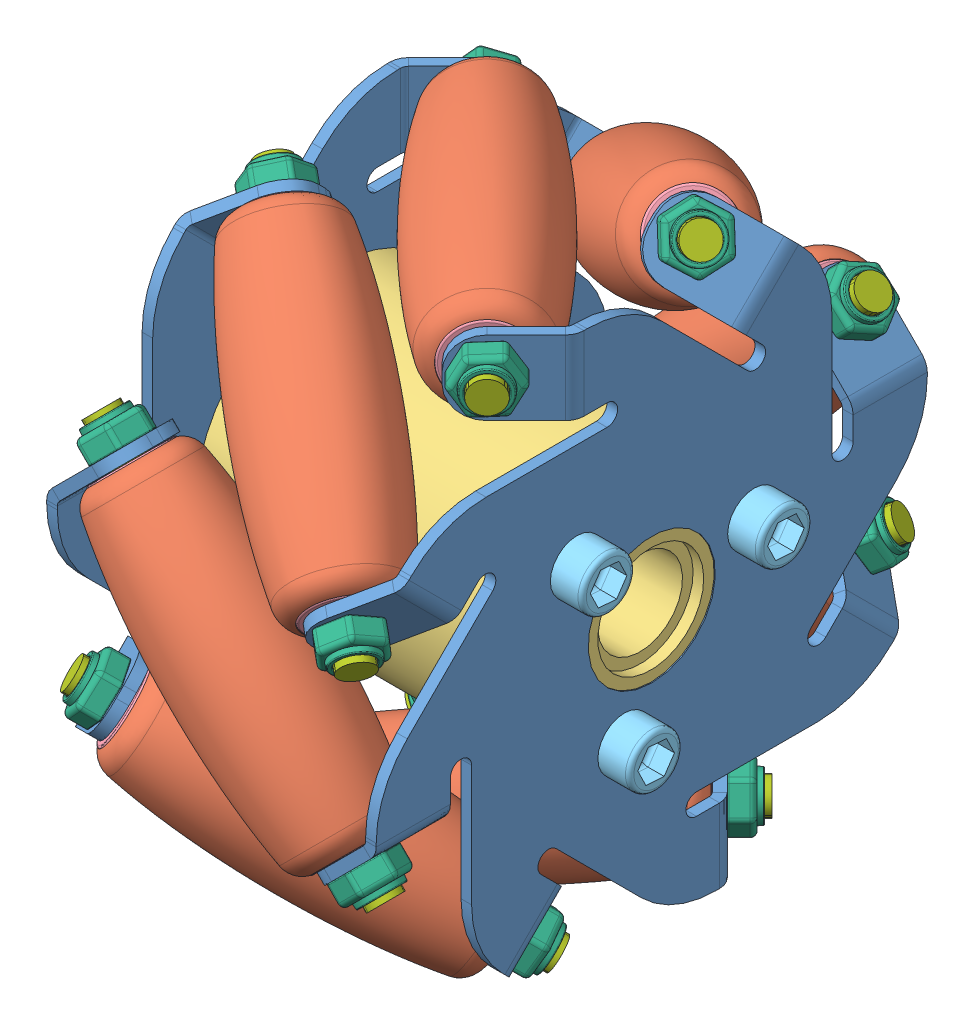
SolidWorks assembly Mecanum_Wheel_60mm_ASM, configuration Varsayılan. Lengths in mm.
Overall size (37 62 62).
57 component instances, 7 part files, 19 mates.
Components (placement in the parent):
- plate_1-1: plate_1 [Varsayılan] at (-26.0247 -30.9199 60) size (7.04 53.75 53.75)
- plate_1-2: plate_1 [Varsayılan] at (3.0696 29.3814 -0.3013) x (-1 0 0) z (0 1 0) size (7.04 53.75 53.75)
- roller-14: roller [Varsayılan] at (-11.1205 15.2872 46.4107) x (0.707107 -0.5 0.5) z (-0.228848 -0.830871 -0.50723) size (29.8 12 12)
- inner_cylinder-1: inner_cylinder [Varsayılan] at (-26.0247 -0.7238 29.8948) x (0 0.707107 -0.707107) z (1 0 0) size (26 26 31)
- liner-2: liner [Varsayılan] at (-0.849 8.0242 53.6738) x (0.666667 0.707107 -0.235702) z (-0.235702 0.5 0.833333) size (7 1 7)
- liner-3: liner [Varsayılan] at (-22.0622 23.0242 38.6738) x (0 -0.707107 -0.707107) z (-0.707107 -0.5 0.5) size (7 1 7)
- liner-4: liner [Varsayılan] at (-22.0622 22.2762 19.3102) x (0 -1 0) z (-0.707107 0 0.707107) size (7 1 7)
- liner-5: liner [Varsayılan] at (-22.0622 8.0552 6.1469) x (0 -0.707107 0.707107) z (-0.707107 0.5 0.5) size (7 1 7)
- liner-6: liner [Varsayılan] at (-22.0622 -11.3084 6.8948) x (0 0 1) z (-0.707107 0.707107 0) size (7 1 7)
- liner-7: liner [Varsayılan] at (-22.0622 -24.4717 21.1158) x (0 0.707107 0.707107) z (-0.707107 0.5 -0.5) size (7 1 7)
- liner-8: liner [Varsayılan] at (-22.0622 -23.7238 40.4794) x (0 1 0) z (-0.707107 0 -0.707107) size (7 1 7)
- liner-9: liner [Varsayılan] at (-22.0622 -9.5028 53.6427) x (0 0.707107 -0.707107) z (-0.707107 -0.5 -0.5) size (7 1 7)
- liner-10: liner [Varsayılan] at (-22.0622 9.8609 52.8948) x (0 0 -1) z (-0.707107 -0.707107 0) size (7 1 7)
- liner-11: liner [Varsayılan] at (-0.849 22.2762 40.5234) x (0.666667 0.333333 -0.666667) z (-0.235702 0.942809 0.235702) size (7 1 7)
- liner-12: liner [Varsayılan] at (-0.849 23.0552 21.1469) x (0.666667 -0.235702 -0.707107) z (-0.235702 0.833333 -0.5) size (7 1 7)
- liner-13: liner [Varsayılan] at (-0.849 9.9048 6.8948) x (0.666667 -0.666667 -0.333333) z (-0.235702 0.235702 -0.942809) size (7 1 7)
- liner-14: liner [Varsayılan] at (-0.849 -9.4717 6.1158) x (0.666667 -0.707107 0.235702) z (-0.235702 -0.5 -0.833333) size (7 1 7)
- liner-15: liner [Varsayılan] at (-0.849 -23.7238 19.2662) x (0.666667 -0.333333 0.666667) z (-0.235702 -0.942809 -0.235702) size (7 1 7)
- liner-16: liner [Varsayılan] at (-0.849 -24.5028 38.6427) x (0.666667 0.235702 0.707107) z (-0.235702 -0.833333 0.5) size (7 1 7)
- liner-17: liner [Varsayılan] at (-0.849 -11.3523 52.8948) x (0.666667 0.666667 0.333333) z (-0.235702 -0.235702 0.942809) size (7 1 7)
- roller-22: roller [Varsayılan] at (-11.1205 22.2762 30.2518) x (0.707107 0 0.707107) z (-0.228848 -0.94618 0.228848) size (29.8 12 12)
- roller-23: roller [Varsayılan] at (-11.1205 15.7922 13.8838) x (0.707107 0.5 0.5) z (-0.228848 -0.50723 0.830871) size (29.8 12 12)
- roller-24: roller [Varsayılan] at (-11.1205 -0.3667 6.8948) x (0.707107 0.707107 0) z (-0.228848 0.228848 0.94618) size (29.8 12 12)
- roller-25: roller [Varsayılan] at (-11.1205 -16.7348 13.3789) x (0.707107 0.5 -0.5) z (-0.228848 0.830871 0.50723) size (29.8 12 12)
- roller-26: roller [Varsayılan] at (-11.1205 -23.7238 29.5377) x (0.707107 0 -0.707107) z (-0.228848 0.94618 -0.228848) size (29.8 12 12)
- roller-27: roller [Varsayılan] at (-11.1205 -17.2397 45.9058) x (0.707107 -0.5 -0.5) z (-0.228848 0.50723 -0.830871) size (29.8 12 12)
- roller-28: roller [Varsayılan] at (-11.1205 -1.0808 52.8948) x (0.707107 -0.707107 0) z (-0.228848 -0.228848 -0.94618) size (29.8 12 12)
- 3x35_screw-2: 3x35_screw [Varsayılan] at (-29.9304 6.3473 36.9659) x (0 0 -1) z (1 0 0) size (5 5 37)
- 3x35_screw-5: 3x35_screw [Varsayılan] at (-29.9304 1.8644 20.2355) x (0 -0.866025 0.5) z (1 0 0) size (5 5 37)
- 3x35_screw-6: 3x35_screw [Varsayılan] at (-29.9304 -10.383 32.483) x (0 0.866025 0.5) z (1 0 0) size (5 5 37)
- 3mm_bolt-1: 3mm_bolt [Varsayılan] at (-27.0247 1.8644 20.2355) x (0 0.765139 -0.643866) z (-1 0 0) size (5.6 5.2 2.5)
- 3mm_bolt-2: 3mm_bolt [Varsayılan] at (-27.0247 -10.383 32.483) x (0 -0.940173 -0.340697) z (-1 0 0) size (5.6 5.2 2.5)
- 3mm_bolt-3: 3mm_bolt [Varsayılan] at (-27.0247 6.3473 36.9659) x (0 0.175035 0.984562) z (-1 0 0) size (5.6 5.2 2.5)
- two_sided_screw-1: two_sided_screw [Varsayılan] at (-24.8906 6.0552 4.1469) x (-0.576606 0.817021 -0.001578) z (0.707107 0.5 0.5) size (3 3 38)
- 3mm_bolt-4: 3mm_bolt [Varsayılan] at (-22.8133 7.5242 5.6158) x (-0.060636 0.747379 -0.661626) z (-0.707107 -0.5 -0.5) size (5.6 5.2 2.5)
- 3mm_bolt-5: 3mm_bolt [Varsayılan] at (-0.1419 23.5552 21.6469) x (0.267213 0.465725 -0.843622) z (0.707107 0.5 0.5) size (5.6 5.2 2.5)
- 3mm_bolt-6: 3mm_bolt [Varsayılan] at (-22.8133 22.2762 18.5591) x (-0.060636 0.996316 0.060636) z (-0.707107 0 -0.707107) size (5.6 5.2 2.5)
- 3mm_bolt-7: 3mm_bolt [Varsayılan] at (-22.8133 23.5552 38.1427) x (-0.060636 0.661626 0.747379) z (-0.707107 0.5 -0.5) size (5.6 5.2 2.5)
- 3mm_bolt-8: 3mm_bolt [Varsayılan] at (-22.8133 10.6119 52.8948) x (-0.060636 -0.060636 0.996316) z (-0.707107 0.707107 0) size (5.6 5.2 2.5)
- 3mm_bolt-9: 3mm_bolt [Varsayılan] at (-22.8133 -8.9717 54.1738) x (-0.060636 -0.747379 0.661626) z (-0.707107 0.5 0.5) size (5.6 5.2 2.5)
- 3mm_bolt-10: 3mm_bolt [Varsayılan] at (-22.8133 -23.7238 41.2305) x (-0.060636 -0.996316 -0.060636) z (-0.707107 0 0.707107) size (5.6 5.2 2.5)
- 3mm_bolt-11: 3mm_bolt [Varsayılan] at (-22.8133 -25.0028 21.6469) x (-0.060636 -0.661626 -0.747379) z (-0.707107 -0.5 0.5) size (5.6 5.2 2.5)
- 3mm_bolt-12: 3mm_bolt [Varsayılan] at (-22.8133 -12.0594 6.8948) x (-0.060636 0.060636 -0.996316) z (-0.707107 -0.707107 0) size (5.6 5.2 2.5)
- 3mm_bolt-13: 3mm_bolt [Varsayılan] at (-0.1419 22.2762 41.2305) x (0.267213 0.925848 -0.267213) z (0.707107 0 0.707107) size (5.6 5.2 2.5)
- 3mm_bolt-14: 3mm_bolt [Varsayılan] at (-0.1419 7.5242 54.1738) x (0.267213 0.843622 0.465725) z (0.707107 -0.5 0.5) size (5.6 5.2 2.5)
- 3mm_bolt-15: 3mm_bolt [Varsayılan] at (-0.1419 -12.0594 52.8948) x (0.267213 0.267213 0.925848) z (0.707107 -0.707107 0) size (5.6 5.2 2.5)
- 3mm_bolt-16: 3mm_bolt [Varsayılan] at (-0.1419 -25.0028 38.1427) x (0.267213 -0.465725 0.843622) z (0.707107 -0.5 -0.5) size (5.6 5.2 2.5)
- 3mm_bolt-17: 3mm_bolt [Varsayılan] at (-0.1419 -23.7238 18.5591) x (0.267213 -0.925848 0.267213) z (0.707107 0 -0.707107) size (5.6 5.2 2.5)
- 3mm_bolt-18: 3mm_bolt [Varsayılan] at (-0.1419 -8.9717 5.6158) x (0.267213 -0.843622 -0.465725) z (0.707107 0.5 -0.5) size (5.6 5.2 2.5)
- 3mm_bolt-19: 3mm_bolt [Varsayılan] at (-0.1419 10.6119 6.8948) x (0.267213 -0.267213 -0.925848) z (0.707107 0.707107 0) size (5.6 5.2 2.5)
- two_sided_screw-2: two_sided_screw [Varsayılan] at (-24.8906 22.2762 16.4817) x (-0.576606 0.578837 0.576606) z (0.707107 0 0.707107) size (3 3 38)
- two_sided_screw-3: two_sided_screw [Varsayılan] at (-24.8906 25.0242 36.6738) x (-0.576606 0.001578 0.817021) z (0.707107 -0.5 0.5) size (3 3 38)
- two_sided_screw-4: two_sided_screw [Varsayılan] at (-24.8906 12.6893 52.8948) x (-0.576606 -0.576606 0.578837) z (0.707107 -0.707107 0) size (3 3 38)
- two_sided_screw-5: two_sided_screw [Varsayılan] at (-24.8906 -7.5028 55.6427) x (-0.576606 -0.817021 0.001578) z (0.707107 -0.5 -0.5) size (3 3 38)
- two_sided_screw-6: two_sided_screw [Varsayılan] at (-24.8906 -23.7238 43.3078) x (-0.576606 -0.578837 -0.576606) z (0.707107 0 -0.707107) size (3 3 38)
- two_sided_screw-7: two_sided_screw [Varsayılan] at (-24.8906 -26.4717 23.1158) x (-0.576606 -0.001578 -0.817021) z (0.707107 0.5 -0.5) size (3 3 38)
- two_sided_screw-8: two_sided_screw [Varsayılan] at (-24.8906 -14.1368 6.8948) x (-0.576606 0.576606 -0.578837) z (0.707107 0.707107 0) size (3 3 38)
Mates (geometry in assembly coordinates):
- Concentric11: concentric anti-aligned: cylinder of plate_1-1 through (-27.0247 -0.7238 29.8948) axis (1 0 0) radius 6; cylinder of plate_1-2 through (4.0696 -0.7238 29.8948) axis (-1 0 0) radius 6
- Concentric16: concentric anti-aligned: cylinder of plate_1-1 through (-22.8133 23.5552 38.1427) axis (0.707107 -0.5 0.5) radius 1.5; cylinder of plate_1-2 through (-0.1419 7.5242 54.1738) axis (-0.707107 0.5 -0.5) radius 1.5
- Concentric18: concentric anti-aligned: cylinder of plate_1-1 through (-27.0247 -0.7238 29.8948) axis (1 0 0) radius 6; cylinder of inner_cylinder-1 through (2.9753 -0.7238 29.8948) axis (-1 0 0) radius 5
- Coincident11: coincident anti-aligned: plane of plate_1-1 through (-26.0247 -12.9438 6.8948) normal (1 0 0); plane of inner_cylinder-1 through (-26.0247 -0.7238 29.8948) normal (-1 0 0)
- Concentric19: concentric anti-aligned: cylinder of plate_1-2 through (4.0696 6.3473 36.9659) axis (-1 0 0) radius 1.5; cylinder of inner_cylinder-1 through (-27.0247 6.3473 36.9659) axis (1 0 0) radius 1.5
- Concentric20: concentric aligned: circle of plate_1-2; circle of roller-14
- Coincident14: coincident anti-aligned: plane of roller-14 through (-1.5561 8.5242 53.1738) normal (0.707107 -0.5 0.5); plane of liner-2 through (-1.5561 8.5242 53.1738) normal (-0.707107 0.5 -0.5)
- Concentric23: concentric aligned: cylinder of roller-14 through (-22.0622 23.0242 38.6738) axis (0.707107 -0.5 0.5) radius 1.5; cylinder of liner-2 through (-1.5561 8.5242 53.1738) axis (0.707107 -0.5 0.5) radius 1.5
- Coincident15: coincident anti-aligned: plane of roller-14 through (-21.3551 22.5242 39.1738) normal (-0.707107 0.5 -0.5); plane of liner-3 through (-21.3551 22.5242 39.1738) normal (0.707107 -0.5 0.5)
- Concentric24: concentric anti-aligned: cylinder of roller-14 through (-22.0622 23.0242 38.6738) axis (0.707107 -0.5 0.5) radius 1.5; cylinder of liner-3 through (-21.3551 22.5242 39.1738) axis (-0.707107 0.5 -0.5) radius 1.5
- Coincident16: coincident anti-aligned: plane of plate_1-2 through (2.4018 -23.5506 17.5016) normal (-0.707107 0.5 -0.5); plane of liner-2 through (-0.849 8.0242 53.6738) normal (0.707107 -0.5 0.5)
- Concentric27: concentric aligned: cylinder of plate_1-2 through (4.0696 6.3473 36.9659) axis (-1 0 0) radius 1.5; cylinder of 3x35_screw-2 through (4.0696 6.3473 36.9659) axis (-1 0 0) radius 1.5
- Coincident18: coincident anti-aligned: plane of plate_1-2 through (4.0696 -23.7238 17.6748) normal (1 0 0); plane of 3x35_screw-2 through (4.0696 6.3473 36.9659) normal (-1 0 0)
- Concentric28: concentric anti-aligned: cylinder of 3x35_screw-5 through (4.0696 1.8644 20.2355) axis (-1 0 0) radius 1.5; cylinder of 3mm_bolt-1 through (-29.0247 1.8644 20.2355) axis (1 0 0) radius 1.5
- Coincident19: coincident anti-aligned: plane of plate_1-1 through (-27.0247 -12.9438 6.8948) normal (-1 0 0); plane of 3mm_bolt-1 through (-27.0247 2.0491 22.5375) normal (1 0 0)
- Concentric29: concentric aligned: cylinder of plate_1-2 through (-0.1419 23.5552 21.6469) axis (-0.707107 -0.5 -0.5) radius 1.5; cylinder of two_sided_screw-1 through (1.9794 25.0552 23.1469) axis (-0.707107 -0.5 -0.5) radius 1.5
- Distance1: distance = 3 mm aligned: plane of two_sided_screw-1 through (1.9794 25.0552 23.1469) normal (0.707107 0.5 0.5); plane of plate_1-2 through (26.1089 -16.6604 24.7382) normal (0.707107 0.5 0.5)
- Coincident21: coincident anti-aligned: circle of plate_1-1; circle of 3mm_bolt-4
- Coincident22: coincident anti-aligned: circle of plate_1-2; circle of 3mm_bolt-5
